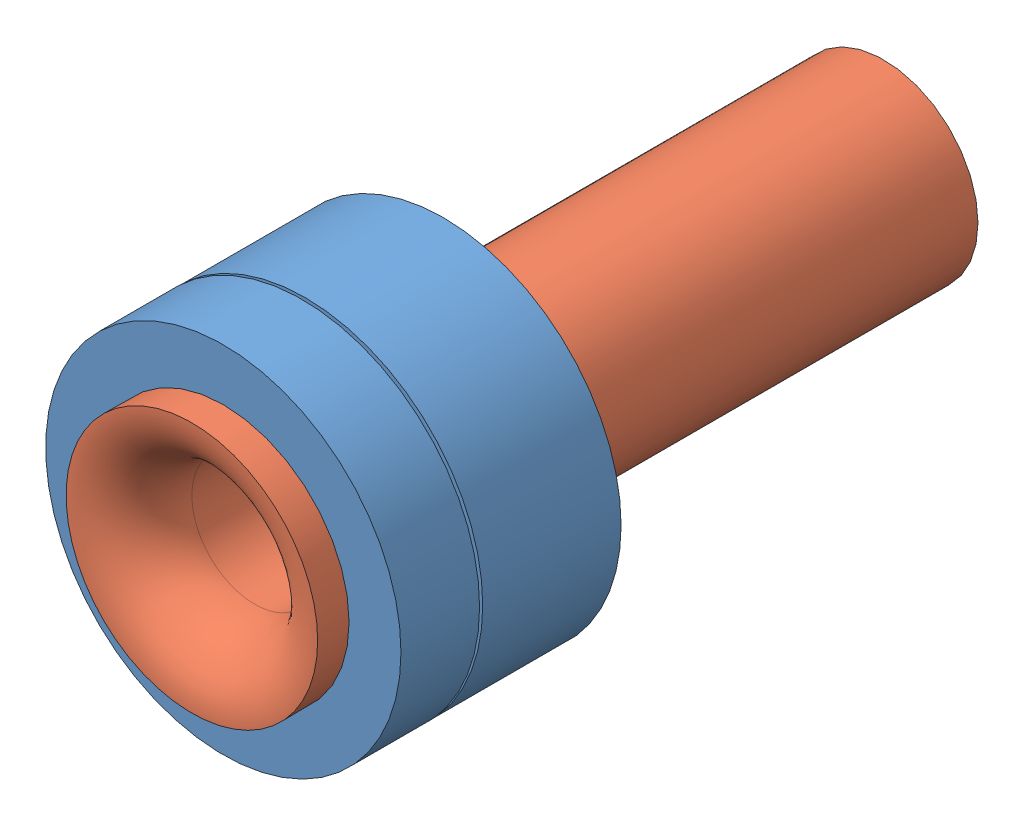
SolidWorks assembly ST-351B V1 - BLACK, configuration Default. Lengths in mm.
Overall size (11.3 11.3 22).
2 component instances, 2 part files, 2 mates.
Components (placement in the parent):
- Insulator-1: Insulator [Default] at origin size (11.3 11.3 7)
- Metal-1: Metal [Default] at (0 0 7.3) size (8 8 22)
Mates (geometry in assembly coordinates):
- Konzentrisch1: concentric: cylinder of Insulator-1 through (0 0 0) axis (0 0 1) radius 3.15; cylinder of Metal-1 through (0 0 -13.7) axis (0 0 1) radius 3
- Deckungsgleich1: coincident anti-aligned: plane of Insulator-1 through (0 0 7.3) normal (0 0 1); plane of Metal-1 through (0 0 7.3) normal (0 0 -1)
